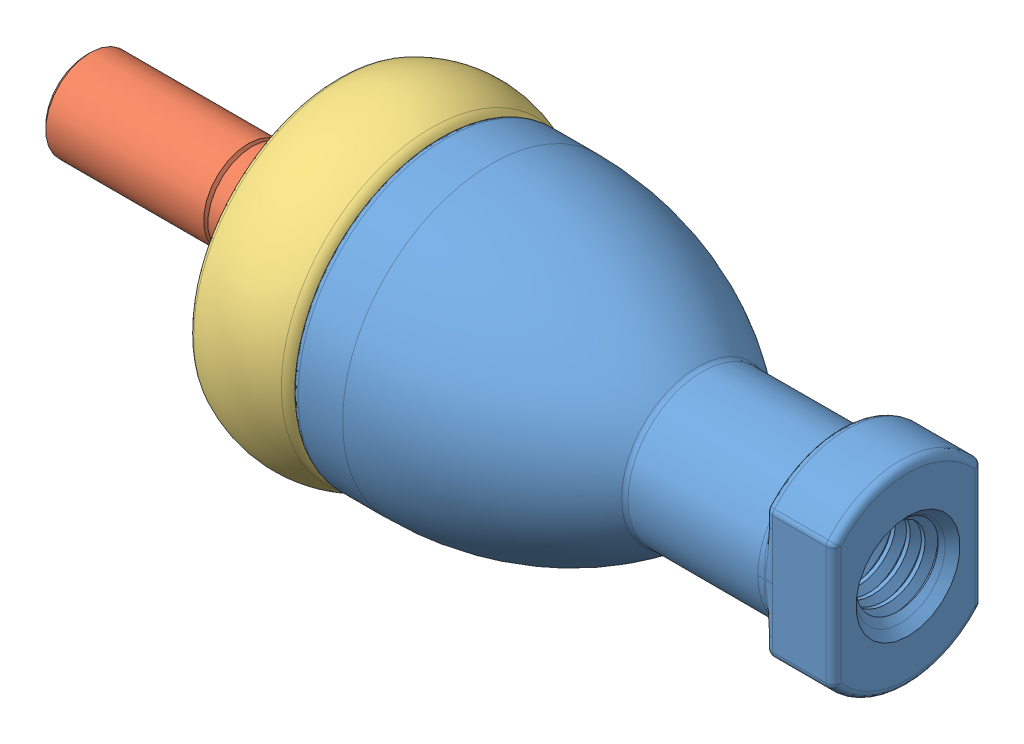
SolidWorks assembly WDS551-766, configuration 551-766. Lengths in mm.
Overall size (55.2 21.5 21.5).
3 component instances, 3 part files, 7 mates.
Components (placement in the parent):
- WDS551-766-P1-1: WDS551-766-P1 [551-7606 (Marketing)] at origin size (31.5 20 20)
- WDS551-766-P2-1: WDS551-766-P2 [551-7606] at (3.5 0 0) size (33.2 12 12)
- WDS551-766-P3-1: WDS551-766-P3 [551-7606] at (-3.5 0 0) x (0 1 0) z (0 0 1) size (21.5 7 21.5)
Mates (geometry in assembly coordinates):
- Coincident1: coincident aligned: plane of 551-76-P1-1 through (0 0 0) normal (0 0 1)
- Coincident2: coincident aligned: plane of 551-76-P1-1 through (0 0 0) normal (0 1 0)
- Coincident3: coincident aligned: plane of 551-76-P1-1 through (0 0 0) normal (1 0 0)
- Concentric1: concentric: sphere of 551-76-P1-1; sphere of WDS551-766-P2-1
- Concentric2: concentric anti-aligned: cylinder of 551-76-P1-1 through (-27.3434 0 0) axis (-1 0 0) radius 10; cylinder of WDS551-766-P3-1 through (2.4571 0 0) axis (1 0 0) radius 5
- Coincident4: coincident anti-aligned: plane of 551-76-P1-1 through (0 0 0) normal (-1 0 0); plane of WDS551-766-P3-1 through (0 5 0) normal (1 0 0)
- Concentric3: concentric aligned: cylinder of 551-76-P1-1 through (-27.3434 0 0) axis (-1 0 0) radius 5; cylinder of WDS551-766-P2-1 through (-6.313 0 0) axis (-1 0 0) radius 3
